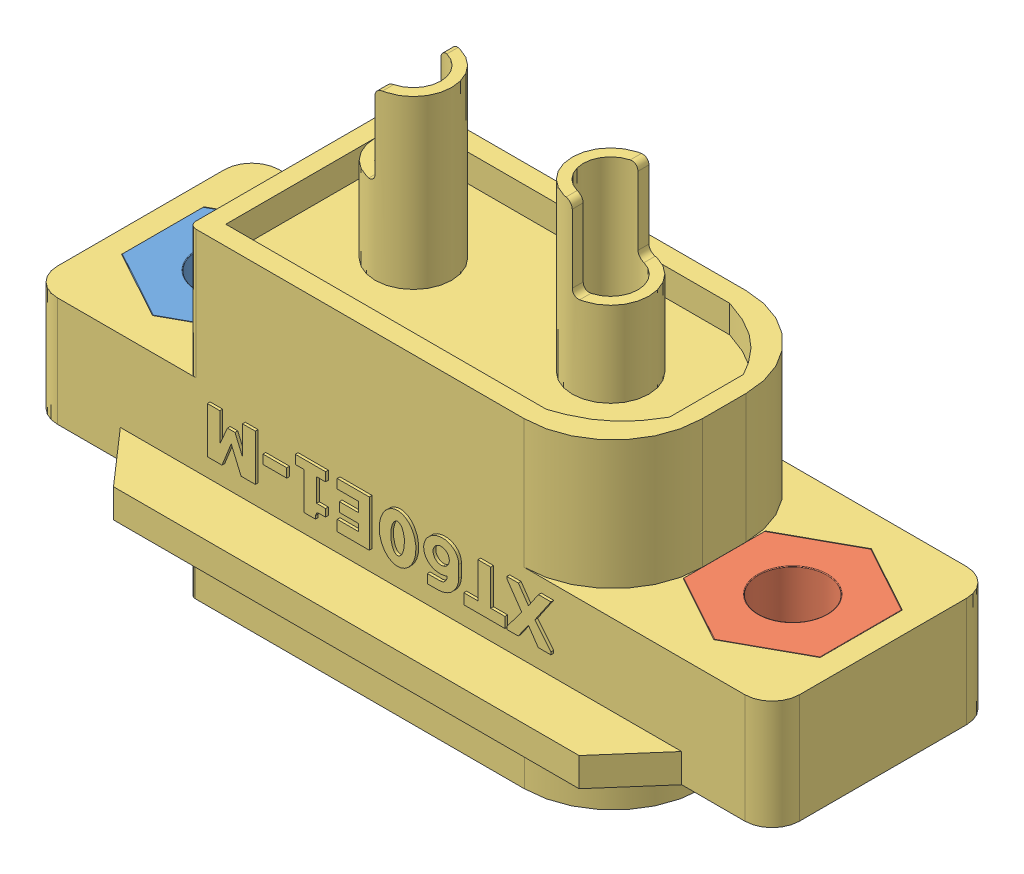
SolidWorks assembly XT60E1-M, configuration Default. Lengths in mm.
Overall size (27.1 16.8 12.1).
4 component instances, 3 part files, 0 mates.
Components (placement in the parent):
- Amass XT60E1-M (2)^XT60E1-M-1: Amass XT60E1-M (2)^XT60E1-M [Default] at origin size (27.1 16.8 12.1) (virtual)
  - M2.5 Nut v1^Amass XT60E1-M (2)_XT60E1-M-1: M2.5 Nut v1^Amass XT60E1-M (2)_XT60E1-M [Default] at (0 2 0) size (5 2 5.75) (virtual)
  - M2.5 Nut v1 (1)^Amass XT60E1-M (2)_XT60E1-M-1: M2.5 Nut v1 (1)^Amass XT60E1-M (2)_XT60E1-M [Default] at (20.5 2 0) size (5 2 5.75) (virtual)
  - Amass XT60E1-M^Amass XT60E1-M (2)_XT60E1-M-1: Amass XT60E1-M^Amass XT60E1-M (2)_XT60E1-M [Default] at origin size (27.1 16.8 12.1) (virtual)
